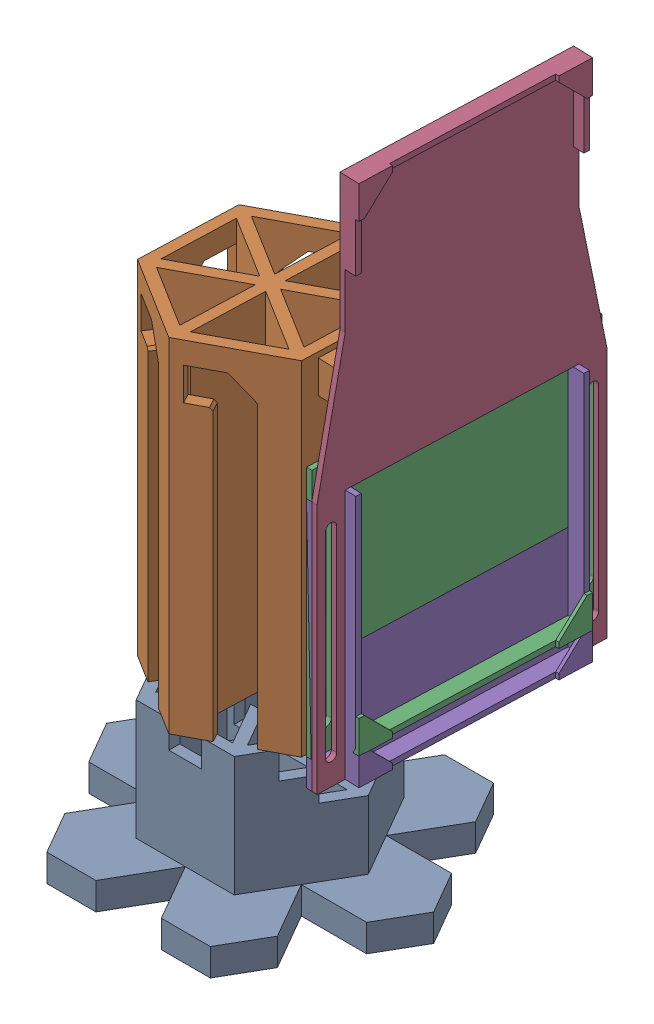
SolidWorks assembly Ensamblaje de torre, configuration Predeterminado. Lengths in mm.
Overall size (142.99 275 118.38).
4 component instances, 4 part files, 9 mates.
Components (placement in the parent):
- base_fija-1: base_fija [Predeterminado] at (-7.9328 -27.6263 0) size (120 54 103.92)
- base_giratoria-1: base_giratoria [Predeterminado] at (-7.9328 -27.6263 0) x (-0.848395 0 -0.529364) z (0.529364 0 -0.848395) size (103.18 130 75.16)
- 1-1: 1 [Predeterminado] at (59.102 147.3737 5.2987) x (0.034245 0 -0.999413) z (0 -1 0) size (103 14.2 92)
- 2-1: 2 [Predeterminado] at (59.102 137.3737 5.2987) x (0.034245 0 -0.999413) z (0 -1 0) size (103 14.2 192)
Mates (geometry in assembly coordinates):
- Concéntrica1: concentric anti-aligned: circle of base_fija-1; circle of base_giratoria-1
- Coincidente1: coincident anti-aligned: plane of base_fija-1 through (-7.9328 26.3737 0) normal (0 1 0); plane of base_giratoria-1 through (-7.9328 26.3737 0) normal (0 -1 0)
- Concéntrica2: concentric aligned: circle of base_giratoria-1; circle of 1-1
- Coincidente2: coincident anti-aligned: plane of base_giratoria-1 through (59.2047 -27.6263 2.3005) normal (0.999413 0 0.034245); plane of 1-1 through (59.102 147.3737 5.2987) normal (-0.999413 0 -0.034245)
- Paralelo2: parallel aligned: plane of base_giratoria-1 through (59.6157 -27.6263 -9.6925) normal (0.034245 0 -0.999413); plane of 1-1 through (64.4415 147.3737 -4.5242) normal (0.034245 0 -0.999413)
- Coincidente3: coincident aligned: line of 1-1 through (67.6218 75.3737 -38.9354) axis (0 1 0); line of 2-1 through (67.6218 65.3737 -38.9354) axis (0 1 0)
- Coincidente4: coincident anti-aligned: plane of 1-1 through (66.0979 147.3737 5.5385) normal (0.999413 0 0.034245); plane of 2-1 through (66.0979 137.3737 5.5385) normal (-0.999413 0 -0.034245)
- Paralelo3: parallel aligned: plane of 1-1 through (64.3343 65.3737 57.0082) normal (-0.034245 0 0.999413); plane of 2-1 through (66.3331 137.3737 57.0767) normal (-0.034245 0 0.999413)
- Distancia1: distance = 10 mm aligned: plane of 2-1 through (68.0967 55.3737 5.6069) normal (0 -1 0); plane of 1-1 through (70.6732 65.3737 47.2196) normal (0 -1 0)
